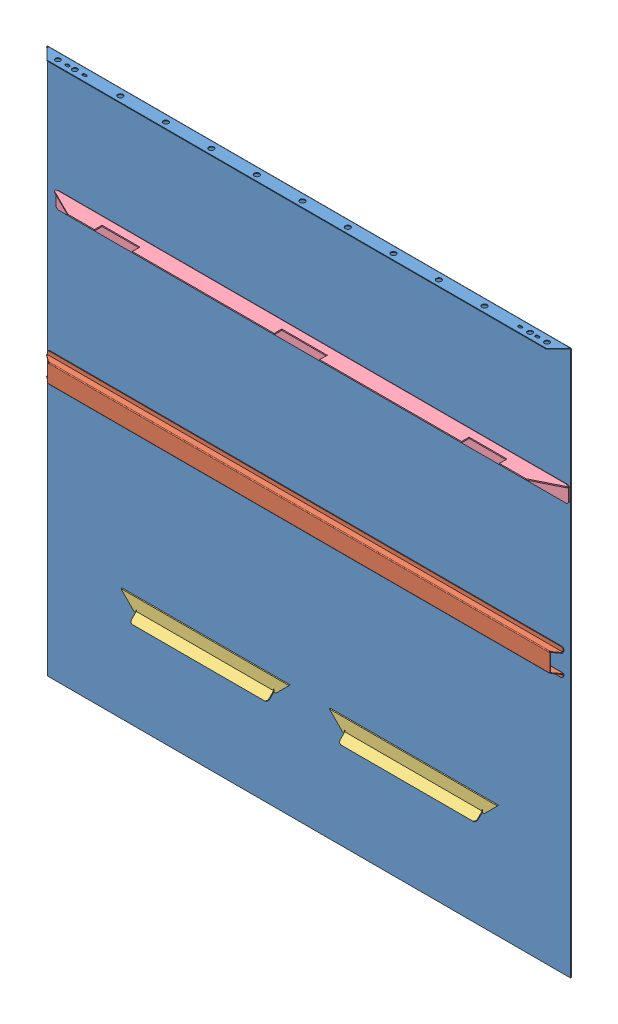
SolidWorks assembly 機體後板, configuration 預設. Lengths in mm.
Overall size (1380 1438.1 45.5).
5 component instances, 4 part files, 12 mates.
Components (placement in the parent):
- LB-A54A-02-6-1: LB-A54A-02-6 [預設] at (-80618.6768 10088.9698 -1) size (1380 1438.1 34.19)
- LB-A54A-02-7-1: LB-A54A-02-7 [預設] at (654.2438 -32.1294 19.8) x (-1 0 0) z (0 0 -1) size (1360 70.4 18.8)
- LB-A54-03-4-1: LB-A54-03-4 [預設] at (-510.6908 -452.7134 1) size (443.37 51.57 20.58)
- LB-A54-03-4-2: LB-A54-03-4 [預設] at (39.1118 -452.7134 1) size (443.37 51.57 20.58)
- LB-A54A-02-8-1: LB-A54A-02-8 [預設] at (-85867.9995 11163.7201 1) size (1352 43.5 43.5)
Mates (geometry in assembly coordinates):
- 重合/共線/共點1: coincident anti-aligned: plane of LB-A54A-02-7-1 through (649.2438 -40.3294 1) normal (0 0 -1); plane of LB-A54A-02-6-1 through (-707.7562 -694.7134 1) normal (0 0 1)
- 重合/共線/共點3: coincident: line of LB-A54A-02-6-1 through (-705.7562 -18.9294 -1) axis (1 0 0); plane of LB-A54A-02-7-1 through (649.2438 -18.9294 1) normal (0 -1 0)
- 重合/共線/共點4: coincident: point of LB-A54A-02-6-1; plane of LB-A54A-02-7-1 through (-705.7562 41.5706 1) normal (-1 0 0)
- 重合/共線/共點5: coincident: plane of LB-A54A-02-6-1 through (-707.7562 -694.7134 1) normal (0 0 1); plane of LB-A54-03-4-1 through (-462.0075 -444.7134 1) normal (0 0 -1)
- 重合/共線/共點6: coincident: line of LB-A54A-02-6-1 through (-58.0241 -395.3134 -1) axis (-1 0 0); plane of LB-A54-03-4-1 through (-67.3241 -395.3134 4) normal (0 1 0)
- 重合/共線/共點8: coincident anti-aligned: plane of LB-A54A-02-6-1 through (-707.7562 -694.7134 1) normal (0 0 1); plane of LB-A54-03-4-2 through (87.7951 -444.7134 1) normal (0 0 -1)
- 重合/共線/共點9: coincident: line of LB-A54A-02-6-1 through (22.5118 -395.3134 -1) axis (1 0 0); plane of LB-A54-03-4-2 through (482.4785 -395.3134 4) normal (0 1 0)
- 重合/共線/共點10: coincident: point of LB-A54A-02-6-1; line of LB-A54-03-4-2 through (482.4785 -395.3134 4) axis (0 0 -1)
- 重合/共線/共點11: coincident anti-aligned: plane of LB-A54A-02-6-1 through (-707.7562 -694.7134 1) normal (0 0 1); plane of LB-A54A-02-8-1 through (-5.7562 -284.3094 1) normal (0 0 -1)
- 重合/共線/共點12: coincident: line of LB-A54A-02-6-1 through (-705.7562 430.1866 -1) axis (1 0 0); plane of LB-A54A-02-8-1 through (-5.7562 430.1866 -707.504) normal (0 1 0)
- 重合/共線/共點13: coincident: point of LB-A54A-02-6-1; plane of LB-A54A-02-8-1 through (670.2438 391.6906 4) normal (1 0 0)
- 重合/共線/共點15: coincident: point of LB-A54A-02-6-1; plane of LB-A54-03-4-1 through (-470.0075 -439.1078 15.927) normal (-1 0 0)
